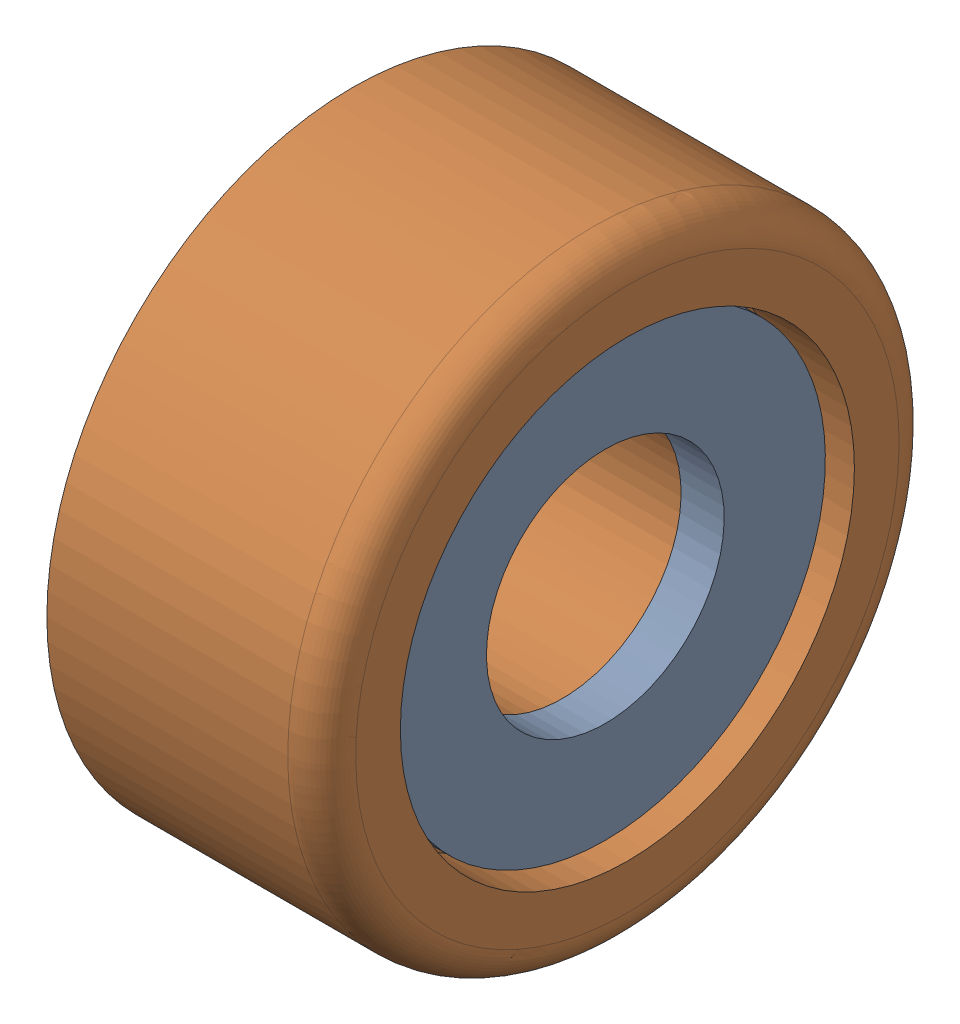
SolidWorks assembly 3,5 mm (Audio White), configuration Default. Lengths in mm.
Overall size (4.05 9 9).
2 component instances, 2 part files, 0 mates.
Components (placement in the parent):
- Part216-1: Part216 [Default] at (32.1699 -0.8638 41.0298) x (0 1 0) z (1 0 0) size (6.48 6.48 0.63)
- Part215-1: Part215 [Default] at (29.0831 -0.8638 41.0298) x (0 1 0) z (1 0 0) size (9 9 4.05)
